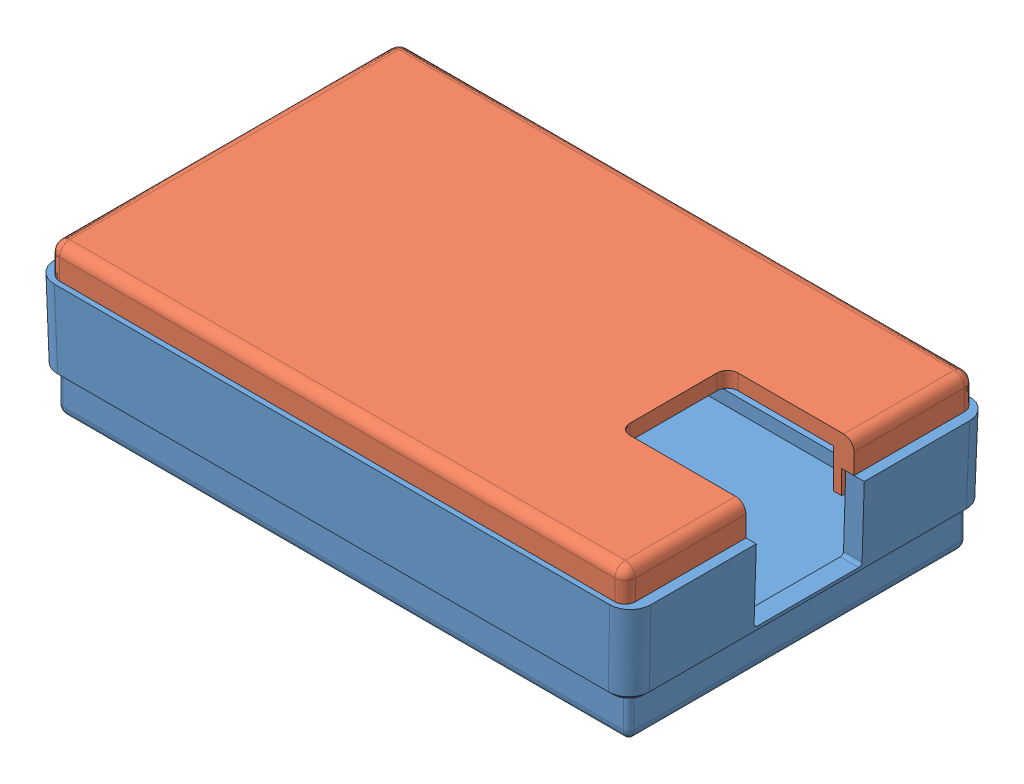
SolidWorks assembly Enclosure-noname, configuration Default. Lengths in mm.
Overall size (58 15 35).
6 component instances, 3 part files, 15 mates.
Components (placement in the parent):
- CaseBase-1: CaseBase [Default] at origin size (58 12 35)
- CaseLid-1: CaseLid [Default] at (0 15 0) x (1 0 0) z (0 0 -1) size (56 5.3 34)
- Spacer-1: Spacer [D=4mm H=2mm] at (24.25 2 12.9) size (4 2 4)
- Spacer-2: Spacer [D=4mm H=2mm] at (24.25 2 -12.9) size (4 2 4)
- Spacer-3: Spacer [D=4mm H=2mm] at (-24.25 2 -12.9) size (4 2 4)
- Spacer-4: Spacer [D=4mm H=2mm] at (-24.25 2 12.9) size (4 2 4)
Mates (geometry in assembly coordinates):
- Coincident1: coincident anti-aligned: plane of CaseBase-1 through (0 12 0) normal (0 1 0); plane of CaseLid-1 through (0 12 0) normal (0 -1 0)
- Coincident2: coincident anti-aligned: plane of CaseBase-1 through (0 0 0) normal (0 0 1); plane of CaseLid-1 through (0 15 0) normal (0 0 -1)
- Coincident3: coincident aligned: plane of CaseBase-1 through (0 0 0) normal (1 0 0); plane of CaseLid-1 through (0 15 0) normal (1 0 0)
- Coincident4: coincident anti-aligned: plane of CaseBase-1 through (0 2 0) normal (0 1 0); plane of SpacerBottom^Enclosure-noname-1 through (24.25 2 12.9) normal (0 -1 0)
- Coincident5: coincident anti-aligned: plane of CaseBase-1 through (0 2 0) normal (0 1 0); plane of SpacerBottom^Enclosure-noname-2 through (24.25 2 -12.9) normal (0 -1 0)
- Coincident6: coincident anti-aligned: plane of CaseBase-1 through (0 2 0) normal (0 1 0); plane of SpacerBottom^Enclosure-noname-3 through (-24.25 2 -12.9) normal (0 -1 0)
- Coincident7: coincident anti-aligned: plane of CaseBase-1 through (0 2 0) normal (0 1 0); plane of SpacerBottom^Enclosure-noname-4 through (-24.25 2 12.9) normal (0 -1 0)
- Tangent1: tangent anti-aligned: plane of CaseBase-1 through (-26.25 4 -14.9) normal (1 0 0); cylinder of SpacerBottom^Enclosure-noname-3 through (-24.25 4 -12.9) axis (0 -1 0) radius 2
- Tangent2: tangent anti-aligned: plane of CaseBase-1 through (26.25 4 -14.9) normal (0 0 1); cylinder of SpacerBottom^Enclosure-noname-3 through (-24.25 4 -12.9) axis (0 -1 0) radius 2
- Tangent3: tangent anti-aligned: plane of CaseBase-1 through (-26.25 4 -14.9) normal (1 0 0); cylinder of SpacerBottom^Enclosure-noname-4 through (-24.25 4 12.9) axis (0 -1 0) radius 2
- Tangent4: tangent anti-aligned: plane of CaseBase-1 through (26.25 4 -14.9) normal (0 0 1); cylinder of SpacerBottom^Enclosure-noname-2 through (24.25 4 -12.9) axis (0 -1 0) radius 2
- Tangent5: tangent anti-aligned: plane of CaseBase-1 through (-26.25 4 14.9) normal (0 0 -1); cylinder of SpacerBottom^Enclosure-noname-4 through (-24.25 4 12.9) axis (0 -1 0) radius 2
- Tangent6: tangent anti-aligned: plane of CaseBase-1 through (-26.25 4 14.9) normal (0 0 -1); cylinder of SpacerBottom^Enclosure-noname-1 through (24.25 4 12.9) axis (0 -1 0) radius 2
- Tangent7: tangent anti-aligned: plane of CaseBase-1 through (26.25 4 14.9) normal (-1 0 0); cylinder of SpacerBottom^Enclosure-noname-2 through (24.25 4 -12.9) axis (0 -1 0) radius 2
- Tangent8: tangent anti-aligned: plane of CaseBase-1 through (26.25 4 14.9) normal (-1 0 0); cylinder of SpacerBottom^Enclosure-noname-1 through (24.25 4 12.9) axis (0 -1 0) radius 2
